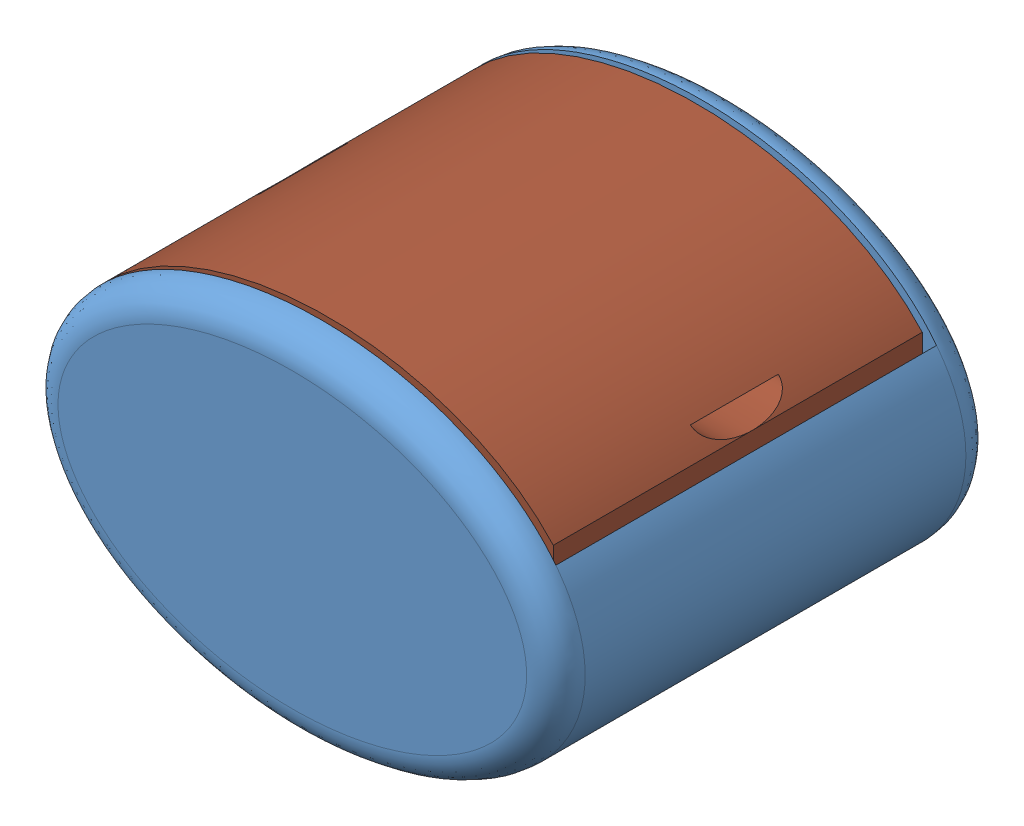
SolidWorks assembly Successful Assembly, configuration Default. Lengths in mm.
Overall size (49.71 34.45 38.1).
30 component instances, 11 part files, 10 mates.
Components (placement in the parent):
- Bottom-1: Bottom [Default] at (-4.0747 21.0508 34.2156) size (49.71 34.45 38.1)
- Flashlight PCB 2-1: Flashlight PCB 2 [Default] at (-19.3987 16.296 36.6032) x (1 0 0) z (0 -1 0) size (33.81 35.83 17.34)
  - Board-1: Board [Default] at origin size (28.59 32.39 0.41)
  - U1-1: U1 [Default] at origin size (3.01 2.91 1.23)
    - SOT23-3-1: SOT23-3 [Default] at (15.3909 26.7763 0) x (0 -1 0) z (0 0 1) size (2.91 3.01 1.23)
    - 4438511424-1: 4438511424 [Default] at (15.494 27.051 0) size (0.25 0.25 0.25)
      - Extruded-1: Extruded [Default] at origin size (0.25 0.25 0.25)
  - R3-1: R3 [Default] at origin size (0.95 1.7 0.9)
    - 4438511040-1: 4438511040 [Default] at (19.685 10.656 0) size (0.95 1.7 0.9)
      - Extruded_2-1: Extruded_2 [Default] at origin size (0.95 1.7 0.9)
  - R2-1: R2 [Default] at origin size (0.95 1.7 0.9)
    - 4438511040-1: 4438511040 [Default] at (17.526 10.656 0) size (0.95 1.7 0.9)
      - Extruded_2-1: Extruded_2 [Default] at origin size (0.95 1.7 0.9)
  - R1-1: R1 [Default] at origin size (0.95 1.7 0.9)
    - 4438511040-1: 4438511040 [Default] at (11.442 10.656 0) size (0.95 1.7 0.9)
      - Extruded_2-1: Extruded_2 [Default] at origin size (0.95 1.7 0.9)
  - R4-1: R4 [Default] at origin size (1.7 0.95 0.9)
    - 4438510848-1: 4438510848 [Default] at (19.443 13.716 0) size (1.7 0.95 0.9)
      - Extruded_3-1: Extruded_3 [Default] at origin size (1.7 0.95 0.9)
  - C2-1: C2 [Default] at origin size (0.95 1.75 1.3)
    - 4438511232-1: 4438511232 [Default] at (12.7 27.748 0) size (0.95 1.75 1.3)
      - Extruded_4-1: Extruded_4 [Default] at origin size (0.95 1.75 1.3)
  - C1-1: C1 [Default] at origin size (1.75 0.95 1.3)
    - 4438510656-1: 4438510656 [Default] at (15.24 23.684 0) size (1.75 0.95 1.3)
      - Extruded_5-1: Extruded_5 [Default] at origin size (1.75 0.95 1.3)
  - ATTiny85-1: ATTiny85 [Default] at origin size (8.25 5.36 2.16)
    - 8S2-1: 8S2 [Default] at (20.8151 20.955 0) x (0 1 0) z (0 0 1) size (8.25 5.36 2.16)
  - Imported-1: Imported [Default] at origin size (27.76 30.96 17.34)
    - keystone-PN1025-7-1: keystone-PN1025-7 [Default] at (15.3925 15.0498 -2.9515) x (1 0 0) z (0 1 0) size (27.76 17.34 30.96)
- Top-1: Top [Default] at (-4.0747 21.0508 34.2156) size (39.43 13.11 32)
Mates (geometry in assembly coordinates):
- Parallel10: parallel: plane of Bottom-1 through (-4.0747 21.0508 69.7756) normal (0 0 -1); plane of Flashlight PCB 2-1/Board-1 through (-18.2557 16.7074 69.7502) normal (0 0 1)
- Distance1: distance = 0.508 mm anti-aligned: plane of Top-1 through (-4.0747 38.2994 69.2676) normal (0 0 1); plane of Bottom-1 through (-4.0747 21.0508 69.7756) normal (0 0 -1)
- Parallel11: parallel anti-aligned: plane of Bottom-1 through (-4.0747 21.0508 69.7756) normal (0 0 -1); plane of Top-1 through (-4.0747 37.9438 69.2676) normal (0 0 1)
- Parallel12: parallel anti-aligned: plane of Bottom-1 through (16.2453 16.4788 69.7756) normal (-1 0 0); plane of Top-1 through (15.5122 37.9438 34.2156) normal (1 0 0)
- Parallel13: parallel: plane of Bottom-1 through (-4.0747 21.0508 69.7756) normal (0 0 -1); plane of Flashlight PCB 2-1/Board-1 through (-18.2557 16.7074 69.7502) normal (0 0 1)
- Distance3: distance = 0.0254 mm: plane of Bottom-1 through (-4.0747 21.0508 69.7756) normal (0 0 -1); plane of Flashlight PCB 2-1/Board-1 through (-18.2557 16.7074 69.7502) normal (0 0 1)
- Parallel14: parallel: plane of Bottom-1 through (-18.6797 12.1608 36.7556) normal (1 0 0); plane of Flashlight PCB 2-1/Board-1 through (-18.2987 16.7074 51.7162) normal (-1 0 0)
- Distance4: distance = 0.381 mm: plane of Flashlight PCB 2-1/Board-1 through (-18.2987 16.7074 51.7162) normal (-1 0 0); plane of Bottom-1 through (-18.6797 12.1608 36.7556) normal (1 0 0)
- Distance5: distance = 0 mm aligned: plane of Top-1 through (10.5303 12.1608 36.7556) normal (-1 0 0); plane of Bottom-1 through (10.5303 12.1608 36.7556) normal (-1 0 0)
- Distance6: distance = 6.7056 mm anti-aligned: plane of Top-1 through (-26.9347 23.1844 72.6526) normal (0 -1 0); plane of Bottom-1 through (16.2453 16.4788 69.7756) normal (0 1 0)
